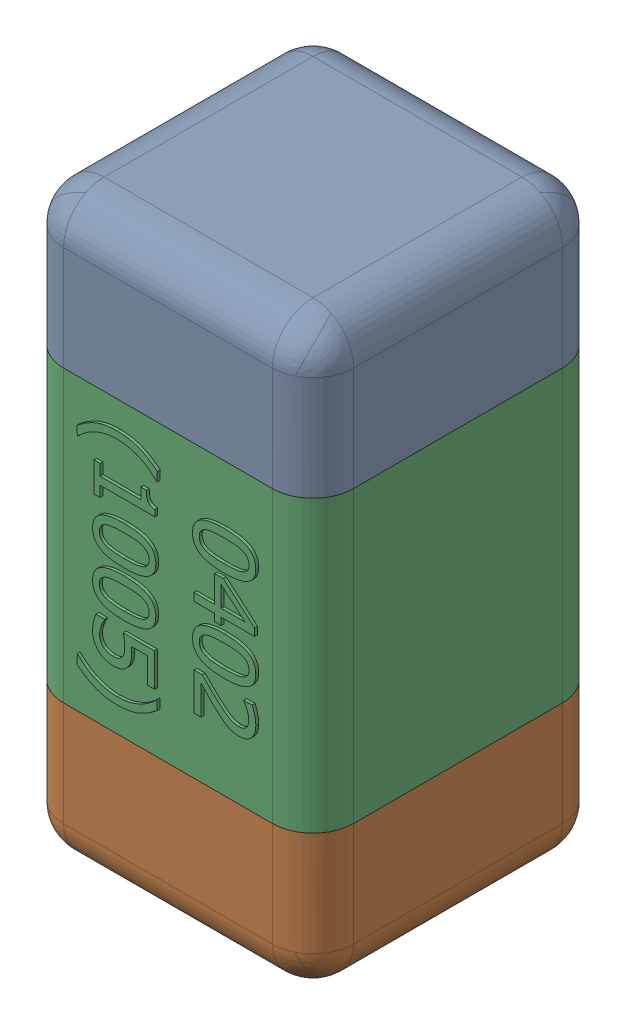
SolidWorks assembly C17, configuration Standard. Lengths in mm.
Overall size (0.51 1.01 0.51).
4 component instances, 3 part files, 0 mates.
Components (placement in the parent):
- C17-subassembly-1-1: C17-subassembly-1 [Standard] at (-4.1 18.0999 0) x (0 -1 0) z (0 0 1) size (1.01 0.51 0.51)
  - User Library-0402_Cap-1: User Library-0402_Cap [Standard] at origin size (0.26 0.51 0.51)
  - User Library-0402_Cap-1-1: User Library-0402_Cap-1 [Standard] at origin size (0.26 0.5 0.51)
  - User Library-0402_Cap-2-1: User Library-0402_Cap-2 [Standard] at origin size (0.5 0.5 0.51)
